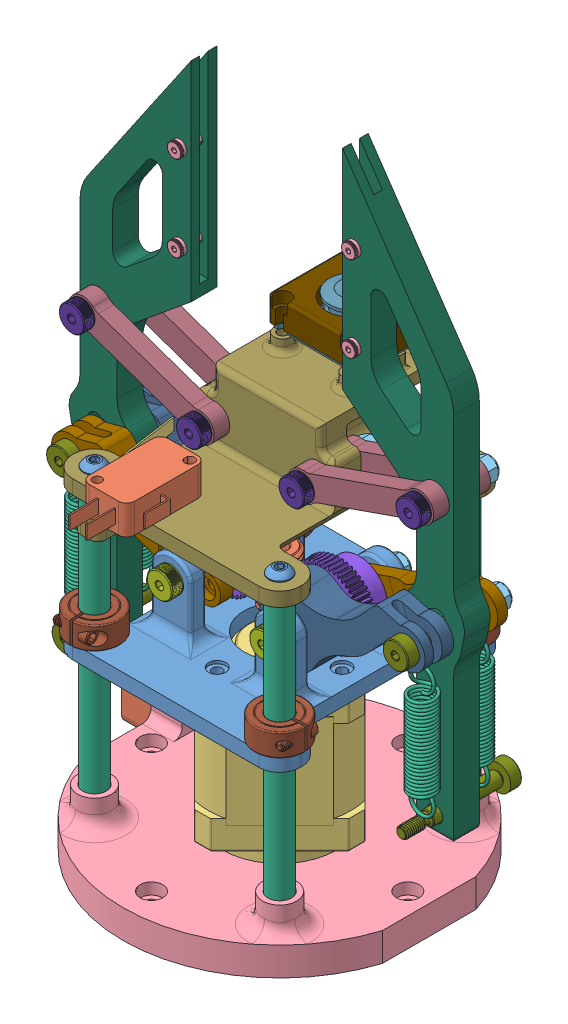
SolidWorks assembly UOR23-ARM-1-A-001, configuration Default. Lengths in mm.
Overall size (138.83 228.92 114.13).
68 component instances, 24 part files, 95 mates.
Components (placement in the parent):
- UOR23-ARM-1-P-002-Mounting_Plate-1: UOR23-ARM-1-P-002-Mounting_Plate [Default] at (27.2151 6.386 103.1364) size (80 29.5 80)
- 57545K624_Steel Worm-1: 57545K624_Steel Worm [57545K624] at (27.2151 28.5546 103.1364) x (-0.707107 0 0.707107) z (0 -1 0) size (12.31 12.28 18.47)
- 17HS19-2004-ME1K-1: 17HS19-2004-ME1K [Default] at (27.2151 -3.614 103.1364) x (0.707107 0 -0.707107) z (0 1 0) size (42.32 60.31 75.5)
- UOR23-ARM-1-P-001-Wrist_Plate-1: UOR23-ARM-1-P-001-Wrist_Plate [Default] at (27.2151 -55.114 103.1364) size (105 21.16 110)
- 94205A230_316 Stainless Steel Nylon-Insert Locknut-2: 94205A230_316 Stainless Steel Nylon-Insert Locknut [94205A230] at (45.2151 28.386 82.8864) x (1 0 0) z (0 1 0) size (7 5.11 8.08)
- UOR23-ARM-1-P-013-1327K124_Rotary Shaft-1: UOR23-ARM-1-P-013-1327K124_Rotary Shaft [1327K124] at (59.7151 5.686 135.6364) x (0.70048 0 -0.713672) z (0 -1 0) size (7.94 7.94 101.6)
- 92981A912_Alloy Steel Shoulder Screws (1)-1: 92981A912_Alloy Steel Shoulder Screws (1) [92981A912] at (9.2151 28.386 102.8864) x (-0.896559 -0.442925 0) z (0 0 1) size (9 9 49.38)
- UOR23-ARM-1-P-011-AID-57545K739-Metal_Worm_Gear-1: UOR23-ARM-1-P-011-AID-57545K739-Metal_Worm_Gear [57545K739] at (9.2151 28.386 103.6364) x (-0.900493 -0.43487 0) z (0 0 -1) size (26.45 26.47 12.01)
- UOR23-ARM-1-P-005-Link_2-1: UOR23-ARM-1-P-005-Link_2 [Default] at (-11.3222 35.547 117.6364) x (-0.329245 -0.944244 0) z (0.944244 -0.329245 0) size (17.4 10 62.14)
- UOR23-ARM-1-P-004-Link_1-1: UOR23-ARM-1-P-004-Link_1 [Default] at (-31.8595 42.7081 88.6364) x (0.329245 0.944244 0) z (0 0 1) size (24.12 60.38 13.84)
- UOR23-ARM-1-P-011-AID-57545K739-Metal_Worm_Gear-2: UOR23-ARM-1-P-011-AID-57545K739-Metal_Worm_Gear [57545K739] at (45.2151 28.386 102.6364) x (0.900493 -0.43487 0) z (0 0 1) size (26.45 26.47 12.01)
- UOR23-ARM-1-P-004-Link_1-2: UOR23-ARM-1-P-004-Link_1 [Default] at (86.2898 42.7081 117.6364) x (-0.329245 0.944244 0) z (0 0 -1) size (24.12 60.38 13.84)
- UOR23-ARM-1-P-005-Link_2-2: UOR23-ARM-1-P-005-Link_2 [Default] at (65.7525 35.547 88.6364) x (0.329245 -0.944244 0) z (-0.944244 -0.329245 0) size (17.4 10 62.14)
- 92981A912_Alloy Steel Shoulder Screws (1)-2: 92981A912_Alloy Steel Shoulder Screws (1) [92981A912] at (45.2151 28.386 102.8864) x (-0.896559 -0.442925 0) z (0 0 1) size (9 9 49.38)
- 6435K52_Clamping Shaft Collar-1: 6435K52_Clamping Shaft Collar [6435K52] at (59.7151 15.3547 135.6364) x (0.066245 0 0.997803) z (0 1 0) size (17.46 17.48 7.98)
- UOR23-ARM-1-P-003-Palm-1: UOR23-ARM-1-P-003-Palm [Default] at (27.2151 56.486 103.1364) size (80 33.4 95.13)
- UOR23-ARM-1-P-006-Link_3-3: UOR23-ARM-1-P-006-Link_3 [Default] at (65.7525 76.647 98.6364) x (0.329245 -0.944244 0) z (0.944244 0.329245 0) size (10 5.5 53.5)
- UOR23-ARM-1-P-006-Link_3-4: UOR23-ARM-1-P-006-Link_3 [Default] at (65.7525 76.647 113.1364) x (0.329245 -0.944244 0) z (0.944244 0.329245 0) size (10 5.5 53.5)
- UOR23-ARM-1-P-010-Camera-1: UOR23-ARM-1-P-010-Camera [Default] at (27.2151 89.886 77.6364) x (0 0 1) z (-1 0 0) size (25 16.3 30)
- UOR23-ARM-1-P-007-Talon_test-1: UOR23-ARM-1-P-007-Talon_test [Default] at (49.7898 173.8081 103.1364) x (0 1 0) z (0 0 -1) size (192 42.84 9)
- UOR23-ARM-1-P-007-Talon_test-3: UOR23-ARM-1-P-007-Talon_test [Default] at (4.6405 173.8081 103.1364) x (0 1 0) z (0 0 1) size (192 42.84 9)
- UOR23-ARM-1-P-006-Link_3-5: UOR23-ARM-1-P-006-Link_3 [Default] at (-11.3222 76.647 98.6364) x (-0.329245 -0.944244 0) z (0.944244 -0.329245 0) size (10 5.5 53.5)
- UOR23-ARM-1-P-006-Link_3-6: UOR23-ARM-1-P-006-Link_3 [Default] at (-11.3222 76.647 113.1364) x (-0.329245 -0.944244 0) z (0.944244 -0.329245 0) size (10 5.5 53.5)
- 94205A230_316 Stainless Steel Nylon-Insert Locknut-3: 94205A230_316 Stainless Steel Nylon-Insert Locknut [94205A230] at (9.2151 28.386 82.8864) x (-1 0 0) z (0 -1 0) size (7 5.11 8.08)
- 92981A050_Alloy Steel Shoulder Screws-1: 92981A050_Alloy Steel Shoulder Screws [92981A050] at (-31.8595 42.7081 121.6364) size (9 9 38.4)
- 94205A230_316 Stainless Steel Nylon-Insert Locknut-4: 94205A230_316 Stainless Steel Nylon-Insert Locknut [94205A230] at (-31.8595 42.7081 88.6364) x (-1 0 0) z (0 -1 0) size (7 5.11 8.08)
- 90265A133_18-8 Stainless Steel Shoulder Screw-1: 90265A133_18-8 Stainless Steel Shoulder Screw [90265A133] at (-31.8595 83.8081 102.6364) x (-0.35485 0.934923 0) z (0 0 1) size (9 9 29.2)
- 90265A133_18-8 Stainless Steel Shoulder Screw-2: 90265A133_18-8 Stainless Steel Shoulder Screw [90265A133] at (9.2151 69.486 102.6364) x (0.984126 -0.177472 0) z (0 0 1) size (9 9 29.2)
- 94205A230_316 Stainless Steel Nylon-Insert Locknut-5: 94205A230_316 Stainless Steel Nylon-Insert Locknut [94205A230] at (-31.8595 83.8081 93.1364) x (-1 0 0) z (0 -1 0) size (7 5.11 8.08)
- 94205A230_316 Stainless Steel Nylon-Insert Locknut-6: 94205A230_316 Stainless Steel Nylon-Insert Locknut [94205A230] at (9.2151 69.486 93.1364) x (-1 0 0) z (0 -1 0) size (7 5.11 8.08)
- UOR23-ARM-1-P-008-Camera_Cover-1: UOR23-ARM-1-P-008-Camera_Cover [Default] at (27.2151 94.486 77.6364) x (0 0 1) z (-1 0 0) size (27 9 32)
- 6435K52_Clamping Shaft Collar-2: 6435K52_Clamping Shaft Collar [6435K52] at (-5.2849 15.3547 135.6364) x (-0.997803 0 0.066245) z (0 1 0) size (17.46 17.48 7.98)
- 6435K52_Clamping Shaft Collar-3: 6435K52_Clamping Shaft Collar [6435K52] at (-5.2849 15.3547 70.6364) x (-0.066245 0 -0.997803) z (0 1 0) size (17.46 17.48 7.98)
- 6435K52_Clamping Shaft Collar-4: 6435K52_Clamping Shaft Collar [6435K52] at (59.7151 15.3547 70.6364) x (0.997803 0 -0.066245) z (0 1 0) size (17.46 17.48 7.98)
- UOR23-ARM-1-P-013-1327K124_Rotary Shaft-2: UOR23-ARM-1-P-013-1327K124_Rotary Shaft [1327K124] at (-5.2849 5.686 135.6364) x (0.713672 0 0.70048) z (0 -1 0) size (7.94 7.94 101.6)
- UOR23-ARM-1-P-013-1327K124_Rotary Shaft-3: UOR23-ARM-1-P-013-1327K124_Rotary Shaft [1327K124] at (-5.2849 5.686 70.6364) x (-0.70048 0 0.713672) z (0 -1 0) size (7.94 7.94 101.6)
- UOR23-ARM-1-P-013-1327K124_Rotary Shaft-4: UOR23-ARM-1-P-013-1327K124_Rotary Shaft [1327K124] at (59.7151 5.686 70.6364) x (-0.713672 0 -0.70048) z (0 -1 0) size (7.94 7.94 101.6)
- 94500A282_316 Stainless Steel Button Head Hex Drive Screws-1: 94500A282_316 Stainless Steel Button Head Hex Drive Screws [94500A282] at (59.7151 63.686 70.6364) x (0.857382 0 -0.51468) z (0 1 0) size (7.6 7.6 18.63)
- 94500A282_316 Stainless Steel Button Head Hex Drive Screws-2: 94500A282_316 Stainless Steel Button Head Hex Drive Screws [94500A282] at (59.7151 -53.314 70.6364) x (-0.995995 0 0.089404) z (0 -1 0) size (7.6 7.6 18.63)
- V_152_1C25-1: V_152_1C25 [Default] at (-30.4349 -38.7551 70.8264) x (0 0 -1) z (1 0 0) size (48.18 24.9 10.3)
  - V_152_1C25_BASE-1: V_152_1C25_BASE [Default] at origin size (37.8 20.43 10.3)
  - V_152_1C25_ACTUATOR-1: V_152_1C25_ACTUATOR [Default] at (-8.6 2.8 -0.2) size (27.28 6.1 4.3)
- 94500A282_316 Stainless Steel Button Head Hex Drive Screws-3: 94500A282_316 Stainless Steel Button Head Hex Drive Screws [94500A282] at (59.7151 63.686 135.6364) x (0.51468 0 0.857382) z (0 1 0) size (7.6 7.6 18.63)
- 94500A282_316 Stainless Steel Button Head Hex Drive Screws-4: 94500A282_316 Stainless Steel Button Head Hex Drive Screws [94500A282] at (-5.2849 63.686 135.6364) x (-0.857382 0 0.51468) z (0 1 0) size (7.6 7.6 18.63)
- 94500A282_316 Stainless Steel Button Head Hex Drive Screws-5: 94500A282_316 Stainless Steel Button Head Hex Drive Screws [94500A282] at (-5.2849 63.686 70.6364) x (-0.51468 0 -0.857382) z (0 1 0) size (7.6 7.6 18.63)
- V_152_1C25-2: V_152_1C25 [Default] at (9.5044 66.636 149.4696) x (0 0 1) z (0 -1 0) size (48.18 24.9 10.3)
  - V_152_1C25_BASE-1: V_152_1C25_BASE [Default] at origin size (37.8 20.43 10.3)
  - V_152_1C25_ACTUATOR-1: V_152_1C25_ACTUATOR [Default] at (-8.6 2.8 -0.2) size (27.28 6.1 4.3)
- 92981A050_Alloy Steel Shoulder Screws-2: 92981A050_Alloy Steel Shoulder Screws [92981A050] at (86.2898 42.7081 121.6364) x (-1 0 0) z (0 0 1) size (9 9 38.4)
- 90265A133_18-8 Stainless Steel Shoulder Screw-3: 90265A133_18-8 Stainless Steel Shoulder Screw [90265A133] at (86.2898 83.8081 102.6364) x (-0.35485 -0.934923 0) z (0 0 1) size (9 9 29.2)
- 94205A230_316 Stainless Steel Nylon-Insert Locknut-7: 94205A230_316 Stainless Steel Nylon-Insert Locknut [94205A230] at (86.2898 83.8081 93.1364) x (1 0 0) z (0 1 0) size (7 5.11 8.08)
- 94205A230_316 Stainless Steel Nylon-Insert Locknut-8: 94205A230_316 Stainless Steel Nylon-Insert Locknut [94205A230] at (86.2898 42.7081 88.6364) x (1 0 0) z (0 1 0) size (7 5.11 8.08)
- 90265A133_18-8 Stainless Steel Shoulder Screw-4: 90265A133_18-8 Stainless Steel Shoulder Screw [90265A133] at (45.2151 69.486 102.6364) x (0.984126 0.177472 0) z (0 0 1) size (9 9 29.2)
- 94205A230_316 Stainless Steel Nylon-Insert Locknut-9: 94205A230_316 Stainless Steel Nylon-Insert Locknut [94205A230] at (45.2151 69.486 93.1364) x (1 0 0) z (0 1 0) size (7 5.11 8.08)
- 92981A770_Alloy Steel Shoulder Screws-1: 92981A770_Alloy Steel Shoulder Screws [92981A770] at (-3.3595 115.523 102.6364) size (5 5 14.26)
- 92981A770_Alloy Steel Shoulder Screws-2: 92981A770_Alloy Steel Shoulder Screws [92981A770] at (-3.3595 145.523 102.6364) size (5 5 14.26)
- 93070A067_Alloy Steel Low-Profile Socket Head Screw-2: 93070A067_Alloy Steel Low-Profile Socket Head Screw [93070A067] at (51.8249 30.6907 96.1864) x (0 0 1) z (-0.73097 0.68241 0) size (12.31 5.5 5.5)
- 93070A067_Alloy Steel Low-Profile Socket Head Screw-3: 93070A067_Alloy Steel Low-Profile Socket Head Screw [93070A067] at (38.6054 26.0812 96.1864) x (0 0 1) z (-0.991971 0.126469 0) size (12.31 5.5 5.5)
- 93070A067_Alloy Steel Low-Profile Socket Head Screw-4: 93070A067_Alloy Steel Low-Profile Socket Head Screw [93070A067] at (47.5199 21.7763 107.6364) x (0 0 -1) z (0.991971 0.126469 0) size (12.31 5.5 5.5)
- 93070A067_Alloy Steel Low-Profile Socket Head Screw-5: 93070A067_Alloy Steel Low-Profile Socket Head Screw [93070A067] at (42.9104 34.9957 107.6364) x (0 0 -1) z (0.991971 0.126469 0) size (12.31 5.5 5.5)
- 7749N332_Corrosion-Resistant Extension Spring with Loop Ends-1: 7749N332_Corrosion-Resistant Extension Spring with Loop Ends [7749N332] at (-32.3595 12.8081 112.6364) x (0 -1 0) z (0 0 1) size (46.53 10.54 10.54)
- 7749N332_Corrosion-Resistant Extension Spring with Loop Ends-2: 7749N332_Corrosion-Resistant Extension Spring with Loop Ends [7749N332] at (-32.3595 12.8081 93.6364) x (0 -1 0) z (0 0 1) size (46.53 10.54 10.54)
- 7749N332_Corrosion-Resistant Extension Spring with Loop Ends-3: 7749N332_Corrosion-Resistant Extension Spring with Loop Ends [7749N332] at (86.7898 12.8081 112.6364) x (0 -1 0) z (0 0 -1) size (46.53 10.54 10.54)
- 7749N332_Corrosion-Resistant Extension Spring with Loop Ends-4: 7749N332_Corrosion-Resistant Extension Spring with Loop Ends [7749N332] at (86.7898 12.8081 93.6364) x (0 -1 0) z (0 0 -1) size (46.53 10.54 10.54)
- 92981A050_Alloy Steel Shoulder Screws-3: 92981A050_Alloy Steel Shoulder Screws [92981A050] at (-31.8595 -12.2919 119.6936) x (0.644824 -0.764331 0) z (0 0 1) size (9 9 38.4)
- 92981A050_Alloy Steel Shoulder Screws-4: 92981A050_Alloy Steel Shoulder Screws [92981A050] at (86.2898 -12.2919 81.5775) x (0.644824 0.764331 0) z (0 0 -1) size (9 9 38.4)
- 92981A770_Alloy Steel Shoulder Screws-3: 92981A770_Alloy Steel Shoulder Screws [92981A770] at (57.7898 115.523 102.6364) size (5 5 14.26)
- 92981A770_Alloy Steel Shoulder Screws-4: 92981A770_Alloy Steel Shoulder Screws [92981A770] at (57.7898 145.523 102.6364) size (5 5 14.26)
Mates (geometry in assembly coordinates):
- Concentric10: concentric anti-aligned: cylinder of UOR23-ARM-1-P-002-Mounting_Plate-1 through (27.2151 11.386 103.1364) axis (0 -1 0) radius 12.5; cylinder of 57545K624_Steel Worm-1 through (27.2151 37.5546 103.1364) axis (0 1 0) radius 2.5
- Concentric23: concentric aligned: cylinder of UOR23-ARM-1-P-002-Mounting_Plate-1 through (27.2151 11.386 103.1364) axis (0 -1 0) radius 12.5; cylinder of 17HS19-2004-ME1K-1 through (27.2151 8.386 103.1364) axis (0 -1 0) radius 11
- Concentric24: concentric aligned: cylinder of UOR23-ARM-1-P-002-Mounting_Plate-1 through (27.2151 11.386 125.0567) axis (0 1 0) radius 1.7; cylinder of 17HS19-2004-ME1K-1 through (27.2151 6.386 125.0567) axis (0 1 0) radius 1.25
- Concentric25: concentric aligned: cylinder of UOR23-ARM-1-P-002-Mounting_Plate-1 through (5.2948 11.386 103.1364) axis (0 1 0) radius 1.7; cylinder of 17HS19-2004-ME1K-1 through (5.2948 6.386 103.1364) axis (0 1 0) radius 1.25
- Coincident21: coincident anti-aligned: plane of UOR23-ARM-1-P-002-Mounting_Plate-1 through (27.2151 6.386 103.1364) normal (0 -1 0); plane of 17HS19-2004-ME1K-1 through (27.2151 6.386 103.1364) normal (0 1 0)
- Parallel12: parallel aligned: plane of 57545K624_Steel Worm-1 through (23.7351 23.6796 99.6564) normal (-0.707107 0 -0.707107); plane of 17HS19-2004-ME1K-1 through (25.8009 -3.614 101.7222) normal (-0.707107 0 -0.707107)
- Coincident24: coincident anti-aligned: plane of 17HS19-2004-ME1K-1 through (27.2151 -45.114 103.1364) normal (0 -1 0); plane of UOR23-ARM-1-P-001-Wrist_Plate-1 through (27.2151 -45.114 103.1364) normal (0 1 0)
- Concentric44: concentric aligned: cylinder of UOR23-ARM-1-P-002-Mounting_Plate-1 through (45.2151 28.386 67.9142) axis (0 0 1) radius 2.7; cylinder of 94205A230_316 Stainless Steel Nylon-Insert Locknut-2 through (45.2151 28.386 78.6435) axis (0 0 1) radius 1.5453
- Parallel17: parallel aligned: plane of 94205A230_316 Stainless Steel Nylon-Insert Locknut-2 through (48.7151 30.4067 77.8864) normal (1 0 0); plane of UOR23-ARM-1-P-002-Mounting_Plate-1 through (52.2151 36.386 88.3864) normal (1 0 0)
- Coincident35: coincident anti-aligned: plane of UOR23-ARM-1-P-002-Mounting_Plate-1 through (52.2151 36.386 82.8864) normal (0 0 -1); plane of 94205A230_316 Stainless Steel Nylon-Insert Locknut-2 through (48.7151 26.3652 82.8864) normal (0 0 1)
- Concentric67: concentric anti-aligned: cylinder of UOR23-ARM-1-P-001-Wrist_Plate-1 through (59.7151 -35.114 135.6364) axis (0 -1 0) radius 4.15; cylinder of UOR23-ARM-1-P-013-1327K124_Rotary Shaft-1 through (59.7151 -45.114 135.6364) axis (0 1 0) radius 3.9688
- Coincident73: coincident anti-aligned: plane of UOR23-ARM-1-P-001-Wrist_Plate-1 through (27.2151 -45.114 103.1364) normal (0 1 0); plane of UOR23-ARM-1-P-013-1327K124_Rotary Shaft-1 through (59.7151 -45.114 135.6364) normal (0 -1 0)
- Concentric68: concentric aligned: cylinder of UOR23-ARM-1-P-002-Mounting_Plate-1 through (59.7151 11.386 135.6364) axis (0 1 0) radius 4.2; cylinder of UOR23-ARM-1-P-013-1327K124_Rotary Shaft-1 through (59.7151 -45.114 135.6364) axis (0 1 0) radius 3.9688
- Concentric71: concentric anti-aligned: cylinder of UOR23-ARM-1-P-002-Mounting_Plate-1 through (9.2151 28.386 67.9142) axis (0 0 1) radius 2.7; cylinder of 92981A912_Alloy Steel Shoulder Screws (1)-1 through (9.2151 28.386 78.3864) axis (0 0 -1) radius 2.5
- Coincident76: coincident anti-aligned: plane of UOR23-ARM-1-P-002-Mounting_Plate-1 through (2.2151 36.386 123.3864) normal (0 0 1); plane of 92981A912_Alloy Steel Shoulder Screws (1)-1 through (7.222 32.4205 123.3864) normal (0 0 -1)
- Concentric72: concentric anti-aligned: cylinder of UOR23-ARM-1-P-002-Mounting_Plate-1 through (-5.2849 11.386 70.6364) axis (0 1 0) radius 4.2; cylinder of UOR23-ARM-1-P-001-Wrist_Plate-1 through (-5.2849 -35.114 70.6364) axis (0 -1 0) radius 4.15
- Concentric73: concentric anti-aligned: cylinder of 92981A912_Alloy Steel Shoulder Screws (1)-1 through (9.2151 28.386 78.3864) axis (0 0 -1) radius 2.5; cylinder of UOR23-ARM-1-P-011-AID-57545K739-Metal_Worm_Gear-1 through (9.2151 28.386 114.3364) axis (0 0 1) radius 2.5
- Concentric74: concentric anti-aligned: cylinder of 92981A912_Alloy Steel Shoulder Screws (1)-1 through (9.2151 28.386 78.3864) axis (0 0 -1) radius 2.5; cylinder of UOR23-ARM-1-P-004-Link_1-1 through (9.2151 28.386 88.6364) axis (0 0 1) radius 2.75
- Concentric75: concentric aligned: cylinder of UOR23-ARM-1-P-011-AID-57545K739-Metal_Worm_Gear-1 through (11.5199 34.9957 101.1364) axis (0 0 -1) radius 1.25; cylinder of UOR23-ARM-1-P-004-Link_1-1 through (11.5199 34.9957 88.6364) axis (0 0 -1) radius 1.75
- Coincident77: coincident anti-aligned: plane of UOR23-ARM-1-P-011-AID-57545K739-Metal_Worm_Gear-1 through (9.2151 28.386 101.1364) normal (0 0 -1); plane of UOR23-ARM-1-P-004-Link_1-1 through (9.2151 28.386 101.1364) normal (0 0 1)
- Concentric76: concentric aligned: cylinder of 92981A912_Alloy Steel Shoulder Screws (1)-1 through (9.2151 28.386 78.3864) axis (0 0 -1) radius 2.5; cylinder of UOR23-ARM-1-P-005-Link_2-1 through (9.2151 28.386 117.6364) axis (0 0 -1) radius 2.75
- Concentric77: concentric anti-aligned: cylinder of UOR23-ARM-1-P-011-AID-57545K739-Metal_Worm_Gear-1 through (2.6054 30.6907 101.1364) axis (0 0 -1) radius 1.25; cylinder of UOR23-ARM-1-P-005-Link_2-1 through (2.6054 30.6907 117.6364) axis (0 0 1) radius 1.8
- Coincident78: coincident anti-aligned: plane of UOR23-ARM-1-P-011-AID-57545K739-Metal_Worm_Gear-1 through (9.2151 28.386 113.1364) normal (0 0 1); plane of UOR23-ARM-1-P-005-Link_2-1 through (-31.8595 42.7081 113.1364) normal (0 0 -1)
- Width1: width anti-aligned: plane of UOR23-ARM-1-P-004-Link_1-1 through (-31.8595 42.7081 88.6364) normal (0 0 -1); plane of UOR23-ARM-1-P-002-Mounting_Plate-1 through (-31.8595 42.7081 117.6364) normal (0 0 1); plane of UOR23-ARM-1-P-005-Link_2-1 through (2.2151 36.386 88.3864) normal (0 0 1); plane of UOR23-ARM-1-P-002-Mounting_Plate-1 through (2.2151 36.386 117.8864) normal (0 0 -1)
- Concentric78: concentric aligned: cylinder of UOR23-ARM-1-P-011-AID-57545K739-Metal_Worm_Gear-2 through (45.2151 28.386 91.9364) axis (0 0 -1) radius 2.5; cylinder of UOR23-ARM-1-P-004-Link_1-2 through (45.2151 28.386 117.6364) axis (0 0 -1) radius 2.75
- Concentric79: concentric aligned: cylinder of UOR23-ARM-1-P-011-AID-57545K739-Metal_Worm_Gear-2 through (42.9104 34.9957 105.1364) axis (0 0 1) radius 1.25; cylinder of UOR23-ARM-1-P-004-Link_1-2 through (42.9104 34.9957 117.6364) axis (0 0 1) radius 1.75
- Concentric80: concentric anti-aligned: cylinder of UOR23-ARM-1-P-011-AID-57545K739-Metal_Worm_Gear-2 through (45.2151 28.386 91.9364) axis (0 0 -1) radius 2.5; cylinder of UOR23-ARM-1-P-005-Link_2-2 through (45.2151 28.386 88.6364) axis (0 0 1) radius 2.75
- Concentric81: concentric anti-aligned: cylinder of UOR23-ARM-1-P-011-AID-57545K739-Metal_Worm_Gear-2 through (38.6054 26.0812 105.1364) axis (0 0 1) radius 1.25; cylinder of UOR23-ARM-1-P-005-Link_2-2 through (38.6054 26.0812 88.6364) axis (0 0 -1) radius 1.8
- Coincident79: coincident anti-aligned: plane of UOR23-ARM-1-P-011-AID-57545K739-Metal_Worm_Gear-2 through (45.2151 28.386 93.1364) normal (0 0 -1); plane of UOR23-ARM-1-P-005-Link_2-2 through (86.2898 42.7081 93.1364) normal (0 0 1)
- Coincident80: coincident anti-aligned: plane of UOR23-ARM-1-P-011-AID-57545K739-Metal_Worm_Gear-2 through (45.2151 28.386 105.1364) normal (0 0 1); plane of UOR23-ARM-1-P-004-Link_1-2 through (45.2151 28.386 105.1364) normal (0 0 -1)
- Concentric82: concentric anti-aligned: cylinder of UOR23-ARM-1-P-002-Mounting_Plate-1 through (45.2151 28.386 67.9142) axis (0 0 1) radius 2.7; cylinder of 92981A912_Alloy Steel Shoulder Screws (1)-2 through (45.2151 28.386 78.3864) axis (0 0 -1) radius 2.5
- Coincident81: coincident anti-aligned: plane of UOR23-ARM-1-P-002-Mounting_Plate-1 through (52.2151 36.386 123.3864) normal (0 0 1); plane of 92981A912_Alloy Steel Shoulder Screws (1)-2 through (43.222 32.4205 123.3864) normal (0 0 -1)
- Concentric83: concentric aligned: cylinder of UOR23-ARM-1-P-011-AID-57545K739-Metal_Worm_Gear-2 through (45.2151 28.386 91.9364) axis (0 0 -1) radius 2.5; cylinder of 92981A912_Alloy Steel Shoulder Screws (1)-2 through (45.2151 28.386 78.3864) axis (0 0 -1) radius 2.5
- Width2: width anti-aligned: plane of UOR23-ARM-1-P-004-Link_1-2 through (86.2898 42.7081 117.6364) normal (0 0 1); plane of UOR23-ARM-1-P-002-Mounting_Plate-1 through (86.2898 42.7081 88.6364) normal (0 0 -1); plane of UOR23-ARM-1-P-005-Link_2-2 through (52.2151 36.386 117.8864) normal (0 0 -1); plane of UOR23-ARM-1-P-002-Mounting_Plate-1 through (52.2151 36.386 88.3864) normal (0 0 1)
- Concentric84: concentric anti-aligned: cylinder of UOR23-ARM-1-P-013-1327K124_Rotary Shaft-1 through (59.7151 -45.114 135.6364) axis (0 1 0) radius 3.9688; cylinder of 6435K52_Clamping Shaft Collar-1 through (59.7151 19.3235 135.6364) axis (0 -1 0) radius 3.9688
- Coincident83: coincident anti-aligned: plane of UOR23-ARM-1-P-002-Mounting_Plate-1 through (27.2151 11.386 103.1364) normal (0 1 0); plane of 6435K52_Clamping Shaft Collar-1 through (59.7151 11.386 135.6364) normal (0 -1 0)
- Concentric85: concentric aligned: cylinder of UOR23-ARM-1-P-013-1327K124_Rotary Shaft-1 through (59.7151 -45.114 135.6364) axis (0 1 0) radius 3.9688; cylinder of UOR23-ARM-1-P-003-Palm-1 through (59.7151 61.486 135.6364) axis (0 1 0) radius 2.4
- Coincident84: coincident anti-aligned: plane of UOR23-ARM-1-P-013-1327K124_Rotary Shaft-1 through (59.7151 56.486 135.6364) normal (0 1 0); plane of UOR23-ARM-1-P-003-Palm-1 through (27.2151 56.486 103.1364) normal (0 -1 0)
- Concentric86: concentric aligned: cylinder of UOR23-ARM-1-P-002-Mounting_Plate-1 through (-5.2849 11.386 135.6364) axis (0 1 0) radius 4.2; cylinder of UOR23-ARM-1-P-003-Palm-1 through (-5.2849 61.486 135.6364) axis (0 1 0) radius 2.4
- Concentric92: concentric anti-aligned: cylinder of UOR23-ARM-1-P-003-Palm-1 through (45.2151 69.486 90.9997) axis (0 0 1) radius 2.7; cylinder of UOR23-ARM-1-P-006-Link_3-3 through (45.2151 69.486 98.6364) axis (0 0 -1) radius 2.75
- Coincident88: coincident anti-aligned: plane of UOR23-ARM-1-P-003-Palm-1 through (3.2151 81.486 98.6364) normal (0 0 -1); plane of UOR23-ARM-1-P-006-Link_3-3 through (45.2151 69.486 98.6364) normal (0 0 1)
- Concentric93: concentric anti-aligned: cylinder of UOR23-ARM-1-P-003-Palm-1 through (45.2151 69.486 90.9997) axis (0 0 1) radius 2.7; cylinder of UOR23-ARM-1-P-006-Link_3-4 through (45.2151 69.486 113.1364) axis (0 0 -1) radius 2.75
- Coincident89: coincident anti-aligned: plane of UOR23-ARM-1-P-003-Palm-1 through (3.2151 81.486 107.6364) normal (0 0 1); plane of UOR23-ARM-1-P-006-Link_3-4 through (45.2151 69.486 107.6364) normal (0 0 -1)
- Coincident90: coincident aligned: plane of UOR23-ARM-1-P-006-Link_3-3 through (84.9728 87.5851 93.1364) normal (-0.329245 0.944244 0); plane of UOR23-ARM-1-P-006-Link_3-4 through (84.9728 87.5851 107.6364) normal (-0.329245 0.944244 0)
- Coincident91: coincident anti-aligned: plane of UOR23-ARM-1-P-003-Palm-1 through (27.2151 89.886 103.1364) normal (0 1 0); plane of UOR23-ARM-1-P-010-Camera-1 through (27.2151 89.886 77.6364) normal (0 -1 0)
- Concentric94: concentric aligned: cylinder of UOR23-ARM-1-P-003-Palm-1 through (39.2151 89.886 65.1364) axis (0 1 0) radius 1.7; cylinder of UOR23-ARM-1-P-010-Camera-1 through (39.2151 89.486 65.1364) axis (0 1 0) radius 1.5
- Concentric95: concentric aligned: cylinder of UOR23-ARM-1-P-003-Palm-1 through (15.2151 89.886 65.1364) axis (0 1 0) radius 1.7; cylinder of UOR23-ARM-1-P-010-Camera-1 through (15.2151 89.486 65.1364) axis (0 1 0) radius 1.5
- Concentric97: concentric anti-aligned: cylinder of UOR23-ARM-1-P-005-Link_2-2 through (86.2898 42.7081 98.6364) axis (0 0 -1) radius 2.75; cylinder of UOR23-ARM-1-P-007-Talon_test-1 through (86.2898 42.7081 98.6364) axis (0 0 1) radius 2.75
- Concentric98: concentric anti-aligned: cylinder of UOR23-ARM-1-P-006-Link_3-3 through (86.2898 83.8081 98.6364) axis (0 0 -1) radius 2.75; cylinder of UOR23-ARM-1-P-007-Talon_test-1 through (86.2898 83.8081 98.6364) axis (0 0 1) radius 2.75
- Width4: width anti-aligned: plane of UOR23-ARM-1-P-007-Talon_test-3 through (4.6405 173.8081 107.6364) normal (0 0 1); plane of UOR23-ARM-1-P-007-Talon_test-3 through (4.6405 173.8081 98.6364) normal (0 0 -1); plane of UOR23-ARM-1-P-004-Link_1-1 through (-31.8595 42.7081 88.6364) normal (0 0 -1); plane of UOR23-ARM-1-P-005-Link_2-1 through (-31.8595 42.7081 117.6364) normal (0 0 1)
- Concentric101: concentric anti-aligned: cylinder of UOR23-ARM-1-P-004-Link_1-1 through (-31.8595 42.7081 88.6364) axis (0 0 1) radius 2.75; cylinder of UOR23-ARM-1-P-007-Talon_test-3 through (-31.8595 42.7081 107.6364) axis (0 0 -1) radius 2.75
- Concentric103: concentric anti-aligned: cylinder of UOR23-ARM-1-P-005-Link_2-1 through (-31.8595 42.7081 107.6364) axis (0 0 1) radius 2.75; cylinder of 92981A050_Alloy Steel Shoulder Screws-1 through (-31.8595 42.7081 83.6364) axis (0 0 -1) radius 2.5
- Coincident93: coincident anti-aligned: plane of UOR23-ARM-1-P-005-Link_2-1 through (-31.8595 42.7081 117.6364) normal (0 0 1); plane of 92981A050_Alloy Steel Shoulder Screws-1 through (-31.8595 38.2081 117.6364) normal (0 0 -1)
- Concentric104: concentric aligned: cylinder of 92981A050_Alloy Steel Shoulder Screws-1 through (-31.8595 42.7081 83.6364) axis (0 0 -1) radius 2.5; cylinder of 94205A230_316 Stainless Steel Nylon-Insert Locknut-4 through (-31.8595 42.7081 82.3664) axis (0 0 -1) radius 2.3041
- Coincident94: coincident anti-aligned: plane of UOR23-ARM-1-P-004-Link_1-1 through (-31.8595 42.7081 88.6364) normal (0 0 -1); plane of 94205A230_316 Stainless Steel Nylon-Insert Locknut-4 through (-35.3595 44.7288 88.6364) normal (0 0 1)
- Concentric105: concentric anti-aligned: cylinder of UOR23-ARM-1-P-006-Link_3-6 through (-31.8595 83.8081 113.1364) axis (0 0 -1) radius 2.75; cylinder of 90265A133_18-8 Stainless Steel Shoulder Screw-1 through (-31.8595 83.8081 117.1364) axis (0 0 1) radius 2.5
- Coincident95: coincident anti-aligned: plane of UOR23-ARM-1-P-006-Link_3-6 through (-31.8595 83.8081 113.1364) normal (0 0 1); plane of 90265A133_18-8 Stainless Steel Shoulder Screw-1 through (-35.7932 82.3151 113.1364) normal (0 0 -1)
- Concentric106: concentric anti-aligned: cylinder of UOR23-ARM-1-P-006-Link_3-6 through (9.2151 69.486 113.1364) axis (0 0 -1) radius 2.75; cylinder of 90265A133_18-8 Stainless Steel Shoulder Screw-2 through (9.2151 69.486 117.1364) axis (0 0 1) radius 2.5
- Coincident96: coincident anti-aligned: plane of UOR23-ARM-1-P-006-Link_3-6 through (-31.8595 83.8081 113.1364) normal (0 0 1); plane of 90265A133_18-8 Stainless Steel Shoulder Screw-2 through (9.9619 73.6267 113.1364) normal (0 0 -1)
- Concentric107: concentric anti-aligned: cylinder of 90265A133_18-8 Stainless Steel Shoulder Screw-1 through (-31.8595 83.8081 117.1364) axis (0 0 1) radius 1.625; cylinder of 94205A230_316 Stainless Steel Nylon-Insert Locknut-5 through (-31.8595 83.8081 86.8664) axis (0 0 -1) radius 2.3041
- Coincident97: coincident anti-aligned: plane of UOR23-ARM-1-P-006-Link_3-5 through (-31.8595 83.8081 93.1364) normal (0 0 -1); plane of 94205A230_316 Stainless Steel Nylon-Insert Locknut-5 through (-35.3595 85.8288 93.1364) normal (0 0 1)
- Concentric108: concentric aligned: cylinder of 90265A133_18-8 Stainless Steel Shoulder Screw-2 through (9.2151 69.486 117.1364) axis (0 0 1) radius 1.625; cylinder of 94205A230_316 Stainless Steel Nylon-Insert Locknut-6 through (9.2151 69.486 88.8935) axis (0 0 1) radius 1.5453
- Coincident98: coincident anti-aligned: plane of UOR23-ARM-1-P-006-Link_3-5 through (-31.8595 83.8081 93.1364) normal (0 0 -1); plane of 94205A230_316 Stainless Steel Nylon-Insert Locknut-6 through (5.7151 71.5067 93.1364) normal (0 0 1)
- Concentric109: concentric aligned: cylinder of UOR23-ARM-1-P-010-Camera-1 through (27.2151 101.986 77.6364) axis (0 -1 0) radius 8; cylinder of UOR23-ARM-1-P-008-Camera_Cover-1 through (27.2151 100.486 77.6364) axis (0 -1 0) radius 9
- Coincident99: coincident anti-aligned: plane of UOR23-ARM-1-P-010-Camera-1 through (27.2151 91.486 77.6364) normal (0 1 0); plane of UOR23-ARM-1-P-008-Camera_Cover-1 through (27.2151 91.486 77.6364) normal (0 -1 0)
- Concentric111: concentric aligned: cylinder of UOR23-ARM-1-P-010-Camera-1 through (39.2151 89.486 65.1364) axis (0 1 0) radius 1.5; cylinder of UOR23-ARM-1-P-008-Camera_Cover-1 through (39.2151 91.486 65.1364) axis (0 1 0) radius 1.7
- Concentric112: concentric aligned: cylinder of UOR23-ARM-1-P-003-Palm-1 through (59.7151 61.486 70.6364) axis (0 1 0) radius 2.4; cylinder of 94500A282_316 Stainless Steel Button Head Hex Drive Screws-1 through (59.7151 63.686 70.6364) axis (0 1 0) radius 3.8
- Coincident100: coincident anti-aligned: plane of UOR23-ARM-1-P-003-Palm-1 through (27.2151 61.486 103.1364) normal (0 1 0); plane of 94500A282_316 Stainless Steel Button Head Hex Drive Screws-1 through (58.4043 61.486 75.8554) normal (0 -1 0)
- Concentric113: concentric aligned: cylinder of UOR23-ARM-1-P-001-Wrist_Plate-1 through (59.7151 -35.114 70.6364) axis (0 -1 0) radius 4.15; cylinder of 94500A282_316 Stainless Steel Button Head Hex Drive Screws-2 through (59.7151 -53.314 70.6364) axis (0 -1 0) radius 3.8
- Coincident101: coincident anti-aligned: plane of UOR23-ARM-1-P-001-Wrist_Plate-1 through (61.9651 -51.114 70.6364) normal (0 -1 0); plane of 94500A282_316 Stainless Steel Button Head Hex Drive Screws-2 through (63.8496 -51.114 74.0806) normal (0 1 0)
- MOST OPEN POSITION: parallel aligned: plane of UOR23-ARM-1-P-003-Palm-1 through (27.2151 61.486 103.1364) normal (0 1 0); plane of UOR23-ARM-1-P-006-Link_3-6
- Coincident103: coincident anti-aligned: plane of UOR23-ARM-1-P-001-Wrist_Plate-1 through (-25.2849 -45.114 119.53) normal (-1 0 0); plane of V_152_1C25-1/V_152_1C25_BASE-1 through (-25.2849 -35.9551 95.8264) normal (1 0 0)
- Bottom LS Concentric114: concentric anti-aligned: cylinder of UOR23-ARM-1-P-001-Wrist_Plate-1 through (-25.2849 -38.7551 70.8264) axis (-1 0 0) radius 2.45; cylinder of V_152_1C25-1/V_152_1C25_BASE-1 through (-35.5849 -38.7551 70.8264) axis (1 0 0) radius 1.55
- Bottom LS: concentric anti-aligned: cylinder of UOR23-ARM-1-P-001-Wrist_Plate-1 through (-25.2849 -44.1559 93.0622) axis (-1 0 0) radius 2.25; cylinder of V_152_1C25-1/V_152_1C25_BASE-1 through (-35.5849 -44.1559 93.0622) axis (1 0 0) radius 1.7
- MOST CLOSED POSITION: parallel anti-aligned: plane of UOR23-ARM-1-P-004-Link_1-1 through (2.2128 52.1404 124.652) normal (1 0 0); plane of UOR23-ARM-1-P-003-Palm-1 through (22.7151 118.109 63.1364) normal (-1 0 0)
- Coincident105: coincident anti-aligned: plane of UOR23-ARM-1-P-003-Palm-1 through (27.2151 61.486 103.1364) normal (0 1 0); plane of V_152_1C25-2/V_152_1C25_BASE-1 through (6.7044 61.486 124.4696) normal (0 -1 0)
- Concentric116: concentric anti-aligned: cylinder of UOR23-ARM-1-P-003-Palm-1 through (9.1097 61.486 144.1113) axis (0 1 0) radius 2.25; cylinder of V_152_1C25-2/V_152_1C25_BASE-1 through (9.1097 71.786 144.1113) axis (0 -1 0) radius 1.55
- Concentric117: concentric anti-aligned: cylinder of UOR23-ARM-1-P-003-Palm-1 through (19.4097 61.486 121.9113) axis (0 1 0) radius 2.25; cylinder of V_152_1C25-2/V_152_1C25_BASE-1 through (19.4097 71.786 121.9113) axis (0 -1 0) radius 1.7
- Concentric119: concentric anti-aligned: cylinder of UOR23-ARM-1-P-007-Talon_test-3 through (-3.3595 115.523 107.6364) axis (0 0 1) radius 2; cylinder of 92981A770_Alloy Steel Shoulder Screws-1 through (-3.3595 115.523 95.6364) axis (0 0 -1) radius 1.5
- Coincident109: coincident anti-aligned: plane of UOR23-ARM-1-P-007-Talon_test-3 through (4.6405 173.8081 107.6364) normal (0 0 1); plane of 92981A770_Alloy Steel Shoulder Screws-1 through (-3.3595 113.023 107.6364) normal (0 0 -1)
- Concentric120: concentric anti-aligned: cylinder of UOR23-ARM-1-P-007-Talon_test-3 through (-3.3595 145.523 107.6364) axis (0 0 1) radius 2; cylinder of 92981A770_Alloy Steel Shoulder Screws-2 through (-3.3595 145.523 95.6364) axis (0 0 -1) radius 1.5
- Coincident110: coincident anti-aligned: plane of UOR23-ARM-1-P-007-Talon_test-3 through (4.6405 173.8081 107.6364) normal (0 0 1); plane of 92981A770_Alloy Steel Shoulder Screws-2 through (-3.3595 143.023 107.6364) normal (0 0 -1)
- Concentric122: concentric anti-aligned: cylinder of UOR23-ARM-1-P-005-Link_2-2 through (51.8249 30.6907 88.6364) axis (0 0 -1) radius 3.4; cylinder of 93070A067_Alloy Steel Low-Profile Socket Head Screw-2 through (51.8249 30.6907 91.1864) axis (0 0 1) radius 2.75
- Coincident111: coincident anti-aligned: plane of UOR23-ARM-1-P-005-Link_2-2 through (52.4175 28.991 91.1864) normal (0 0 -1); plane of 93070A067_Alloy Steel Low-Profile Socket Head Screw-2 through (53.7015 32.7008 91.1864) normal (0 0 1)
- Concentric123: concentric anti-aligned: cylinder of UOR23-ARM-1-P-005-Link_2-2 through (38.6054 26.0812 88.6364) axis (0 0 -1) radius 3.4; cylinder of 93070A067_Alloy Steel Low-Profile Socket Head Screw-3 through (38.6054 26.0812 91.1864) axis (0 0 1) radius 2.75
- Coincident112: coincident anti-aligned: plane of UOR23-ARM-1-P-005-Link_2-2 through (39.1981 24.3816 91.1864) normal (0 0 -1); plane of 93070A067_Alloy Steel Low-Profile Socket Head Screw-3 through (38.9532 28.8092 91.1864) normal (0 0 1)
- Concentric124: concentric anti-aligned: cylinder of UOR23-ARM-1-P-004-Link_1-2 through (42.9104 34.9957 117.6364) axis (0 0 1) radius 3.4; cylinder of 93070A067_Alloy Steel Low-Profile Socket Head Screw-5 through (42.9104 34.9957 112.6364) axis (0 0 -1) radius 2.75
- Coincident114: coincident anti-aligned: plane of UOR23-ARM-1-P-004-Link_1-2 through (42.3342 36.6481 112.6364) normal (0 0 1); plane of 93070A067_Alloy Steel Low-Profile Socket Head Screw-5 through (42.5626 37.7236 112.6364) normal (0 0 -1)
- Concentric125: concentric anti-aligned: cylinder of UOR23-ARM-1-P-004-Link_1-2 through (47.5199 21.7763 117.6364) axis (0 0 1) radius 3.4; cylinder of 93070A067_Alloy Steel Low-Profile Socket Head Screw-4 through (47.5199 21.7763 112.6364) axis (0 0 -1) radius 2.75
- Coincident115: coincident anti-aligned: plane of UOR23-ARM-1-P-004-Link_1-2 through (46.9437 23.4287 112.6364) normal (0 0 1); plane of 93070A067_Alloy Steel Low-Profile Socket Head Screw-4 through (47.1721 24.5042 112.6364) normal (0 0 -1)
- Parallel18: parallel anti-aligned: plane of UOR23-ARM-1-P-007-Talon_test-3 through (-38.3595 173.8081 107.6364) normal (-1 0 0); plane of 7749N332_Corrosion-Resistant Extension Spring with Loop Ends-1 through (-32.3595 12.8081 112.6364) normal (1 0 0)
- Distance1: distance = 31 mm aligned: plane of 7749N332_Corrosion-Resistant Extension Spring with Loop Ends-1 through (-32.3595 12.8081 112.6364) normal (0 -1 0); plane of UOR23-ARM-1-P-007-Talon_test-3 through (4.6405 -18.1919 107.6364) normal (0 -1 0)
- Distance2: distance = 5 mm aligned: plane of 7749N332_Corrosion-Resistant Extension Spring with Loop Ends-1 through (-32.3595 12.8081 112.6364) normal (0 0 1); plane of UOR23-ARM-1-P-007-Talon_test-3 through (4.6405 173.8081 107.6364) normal (0 0 1)
- Distance3: distance = 6 mm anti-aligned: plane of 7749N332_Corrosion-Resistant Extension Spring with Loop Ends-1 through (-32.3595 12.8081 112.6364) normal (1 0 0); plane of UOR23-ARM-1-P-007-Talon_test-3 through (-38.3595 173.8081 107.6364) normal (-1 0 0)
- Concentric126: concentric aligned: cylinder of UOR23-ARM-1-P-007-Talon_test-3 through (-31.8595 -12.2919 107.6364) axis (0 0 -1) radius 2.75; cylinder of 92981A050_Alloy Steel Shoulder Screws-3 through (-31.8595 -12.2919 81.6936) axis (0 0 -1) radius 2.5
